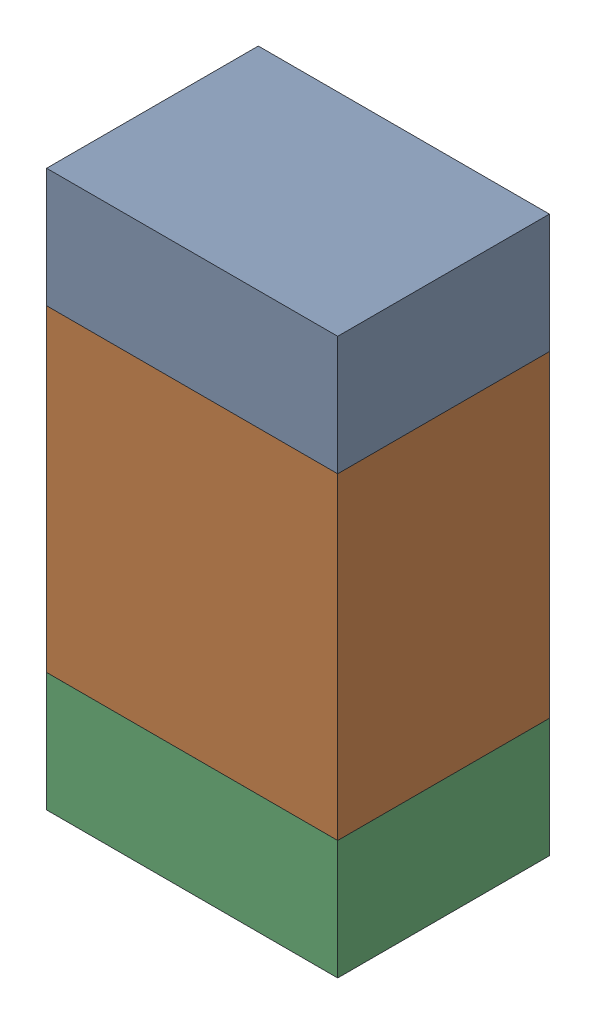
SolidWorks assembly R701PCB, configuration Default. Lengths in mm.
Overall size (0.55 1.05 0.4).
6 component instances, 2 part files, 0 mates.
Components (placement in the parent):
- 846483288-1: 846483288 [Default] at (115.8999 124.1124 -2.0638) size (0.55 0.22 0.4)
  - Extruded_12-1: Extruded_12 [Default] at origin size (0.55 0.22 0.4)
- 846483424-1: 846483424 [Default] at (115.8999 123.6999 -2.0638) size (0.55 0.6 0.4)
  - Extruded_13-1: Extruded_13 [Default] at origin size (0.55 0.6 0.4)
- 846483288-2: 846483288 [Default] at (115.8999 123.2874 -2.0638) size (0.55 0.22 0.4)
  - Extruded_12-1: Extruded_12 [Default] at origin size (0.55 0.22 0.4)
